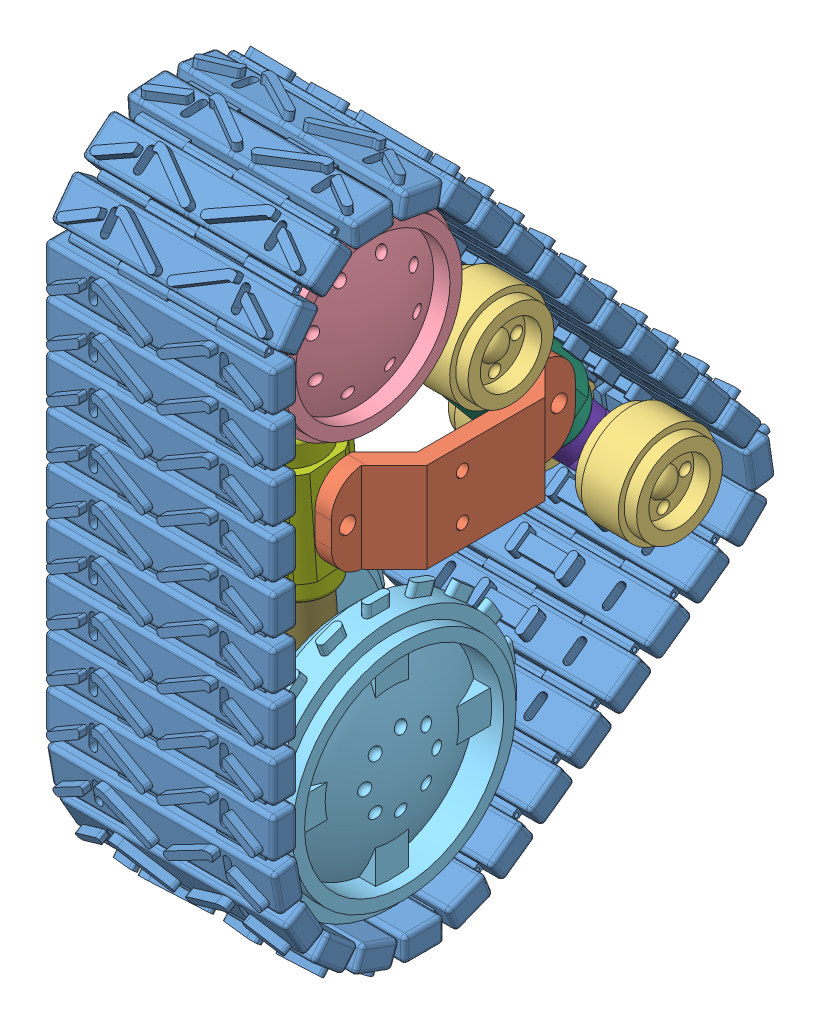
SolidWorks assembly Right Side Drive Train, configuration Default. Lengths in mm.
Overall size (45.17 135.4 102.97).
53 component instances, 12 part files, 148 mates.
Components (placement in the parent):
- Track segment-1: Track segment [Default] at origin size (45.17 8.87 11.14)
- Track segment-2: Track segment [Default] at (0 1.7763 10.0644) x (1 0 0) z (0 0.34232 0.939583) size (45.17 8.87 11.14)
- Track segment-3: Track segment [Default] at (0 34.1905 29.8413) x (1 0 0) z (0 1 0) size (45.17 8.87 11.14)
- Track segment-4: Track segment [Default] at (0 43.7144 29.8413) x (1 0 0) z (0 1 0) size (45.17 8.87 11.14)
- Track segment-5: Track segment [Default] at (0 53.2383 29.8413) x (1 0 0) z (0 1 0) size (45.17 8.87 11.14)
- Track segment-6: Track segment [Default] at (0 6.8872 18.9134) x (1 0 0) z (0 0.642788 0.766044) size (45.17 8.87 11.14)
- Track segment-7: Track segment [Default] at (0 14.7157 25.4824) x (1 0 0) z (0 0.866025 0.5) size (45.17 8.87 11.14)
- Track segment-8: Track segment [Default] at (0 24.3188 28.9776) x (1 0 0) z (0 0.984808 0.173648) size (45.17 8.87 11.14)
- Track segment-9: Track segment [Default] at (0 62.7622 29.8413) x (1 0 0) z (0 1 0) size (45.17 8.87 11.14)
- Track segment-10: Track segment [Default] at (0 72.2861 29.8413) x (1 0 0) z (0 1 0) size (45.17 8.87 11.14)
- Track segment-11: Track segment [Default] at (0 81.81 29.8413) x (1 0 0) z (0 1 0) size (45.17 8.87 11.14)
- Track segment-12: Track segment [Default] at (0 91.3339 29.8413) x (1 0 0) z (0 1 0) size (45.17 8.87 11.14)
- Track segment-13: Track segment [Default] at (0 100.8578 29.8413) x (1 0 0) z (0 1 0) size (45.17 8.87 11.14)
- Track segment-14: Track segment [Default] at (0 110.3817 29.8413) x (1 0 0) z (0 1 0) size (45.17 8.87 11.14)
- Track segment-15: Track segment [Default] at (0 127.7384 19.6963) x (1 0 0) z (0 0.642298 -0.766455) size (45.17 8.87 11.14)
- Track segment-16: Track segment [Default] at (0 131.6664 9.8979) x (1 0 0) z (0 0.064998 -0.997885) size (45.17 8.87 11.14)
- Track segment-17: Track segment [Default] at (0 131.1108 -0.123) x (1 0 0) z (0 -0.174908 -0.984585) size (45.17 8.87 11.14)
- Track segment-18: Track segment [Default] at (0 126.1238 -9.4271) x (1 0 0) z (0 -0.723087 -0.690757) size (45.17 8.87 11.14)
- Track segment-19: Track segment [Default] at (0 118.8782 -15.8648) x (1 0 0) z (0 -0.771041 -0.636786) size (45.17 8.87 11.14)
- Track segment-20: Track segment [Default] at (0 111.5349 -21.9295) x (1 0 0) z (0 -0.771041 -0.636786) size (45.17 8.87 11.14)
- Track segment-21: Track segment [Default] at (0 82.1919 -46.2013) x (1 0 0) z (0 -0.767095 -0.641534) size (45.17 8.87 11.14)
- Track segment-22: Track segment [Default] at (0 120.4147 26.5585) x (1 0 0) z (0 0.806583 -0.591121) size (45.17 8.87 11.14)
- Track segment-23: Track segment [Default] at (0 34.4794 -57.6062) x (1 0 0) z (0 -0.582062 0.813145) size (45.17 8.87 11.14)
- Track segment-24: Track segment [Default] at (0 104.1916 -27.9942) x (1 0 0) z (0 -0.771041 -0.636786) size (45.17 8.87 11.14)
- Track segment-25: Track segment [Default] at (0 96.8483 -34.0588) x (1 0 0) z (0 -0.77104 -0.636786) size (45.17 8.87 11.14)
- Track segment-26: Track segment [Default] at (0 89.505 -40.1235) x (1 0 0) z (0 -0.77104 -0.636786) size (45.17 8.87 11.14)
- Track segment-27: Track segment [Default] at (0 74.8862 -52.3112) x (1 0 0) z (0 -0.767095 -0.641534) size (45.17 8.87 11.14)
- Track segment-28: Track segment [Default] at (0 67.5805 -58.4211) x (1 0 0) z (0 -0.767095 -0.641534) size (45.17 8.87 11.14)
- Track segment-29: Track segment [Default] at (0 60.2747 -64.531) x (1 0 0) z (0 -0.767095 -0.641534) size (45.17 8.87 11.14)
- Track segment-30: Track segment [Default] at (0 50.7132 -68.8203) x (1 0 0) z (0 -0.989231 -0.146359) size (45.17 8.87 11.14)
- Track segment-31: Track segment [Default] at (0 40.5787 -65.4426) x (1 0 0) z (0 -0.703629 0.710567) size (45.17 8.87 11.14)
- Track segment-32: Track segment [Default] at (0 28.9359 -49.8619) x (1 0 0) z (0 -0.582062 0.813145) size (45.17 8.87 11.14)
- Track segment-33: Track segment [Default] at (0 17.8489 -34.3733) x (1 0 0) z (0 -0.582062 0.813145) size (45.17 8.87 11.14)
- Track segment-34: Track segment [Default] at (0 23.3924 -42.1176) x (1 0 0) z (0 -0.582062 0.813145) size (45.17 8.87 11.14)
- Track segment-35: Track segment [Default] at (0 12.3054 -26.6289) x (1 0 0) z (0 -0.582062 0.813145) size (45.17 8.87 11.14)
- Track segment-36: Track segment [Default] at (0 6.7619 -18.8846) x (1 0 0) z (0 -0.582062 0.813144) size (45.17 8.87 11.14)
- Track segment-37: Track segment [Default] at (0 1.9422 -10.0819) x (1 0 0) z (0 -0.371493 0.928436) size (45.17 8.87 11.14)
- Bracket-1: Bracket [Default] at (12.0993 68.7945 -17.7388) x (0 1 0) z (-1 0 0) size (17.74 48.1 9.68)
- Tensioner Small-1: Tensioner Small [Default] at (-12.5006 89.8246 -21.0494) x (0 -0.325213 -0.945641) z (-1 0 0) size (19.33 19.33 12.1)
- Tensioner Large-1: Tensioner Large [Default] at (12.4939 108.1911 6.1736) x (0 -0.888344 -0.459179) z (1 0 0) size (37.66 37.66 12.1)
- Drive Sprocket-1: Drive Sprocket [Default] at (12.907 29.4005 0) x (0 0 1) z (1 0 0) size (53.82 53.8 11.29)
- Cylinder Small-1: Cylinder Small [Default] at (0.0013 68.7945 -38.5642) x (0 -0.768404 -0.639964) z (1 0 0) size (29.03 16.13 14.52)
- Cylinder Large-1: Cylinder Large [Default] at (0.0013 68.7945 3.0867) x (0 -0.996944 -0.078115) z (1 0 0) size (29.03 17.74 14.52)
- Axle short-1: Axle short [Default] at (0.0013 69.8778 -37.6621) x (0 0.768404 0.639964) z (-1 0 0) size (61.59 9.68 12.1)
- Shock Absorber Guide-1: Shock Absorber Guide [Default] at (-10.4838 68.7945 17.1387) x (0 1 0) z (-1 0 0) size (25.81 15.73 9.28)
- Shock Absorber Pivot-1: Shock Absorber Pivot [Default] at (-9.6787 68.7945 3.0867) x (0 1 0) z (-1 0 0) size (19.38 11.58 8.47)
- Shock Absorber Spring-1: Shock Absorber Spring [Default] at (-12.5006 68.7945 20.9691) x (0.879385 -0.476111 0) z (0.476111 0.879385 0) size (5.09 14.18 4.84)
- Tensioner Small-2: Tensioner Small [Default] at (12.5031 89.8246 -21.0494) x (0 -1 0.00019) z (1 0 0) size (19.33 19.33 12.1)
- Tensioner Large-2: Tensioner Large [Default] at (-12.4914 108.1911 6.1736) x (0 -0.876526 0.481354) z (-1 0 0) size (37.66 37.66 12.1)
- Drive Sprocket-2: Drive Sprocket [Default] at (-12.9045 29.4005 0) x (0 0 1) z (-1 0 0) size (53.82 53.8 11.29)
- Tensioner Small-3: Tensioner Small [Default] at (-12.5006 49.9309 -54.2748) x (0 1 0) z (-1 0 0) size (19.33 19.33 12.1)
- Tensioner Small-4: Tensioner Small [Default] at (12.5031 49.9309 -54.2748) x (0 -1 0) z (1 0 0) size (19.33 19.33 12.1)
- Axle long-1: Axle long [Default] at (0.0013 68.7958 3.0868) x (0 -0.996944 -0.078115) z (1 0 0) size (90.32 12.9 13.71)
Mates (geometry in assembly coordinates):
- Concentric61: concentric: cylinder of assembly; cylinder of assembly; cylinder of Track segment-1 through (-9.6774 2.4194 4.7619) axis (1 0 0) radius 0.4039; cylinder of Track segment-2 through (-9.6774 2.4194 4.7619) axis (-1 0 0) radius 0.4039
- Coincident54: coincident: plane of assembly; plane of assembly; plane of Track segment-1 through (-9.6774 2.4194 4.7619) normal (-1 0 0); plane of Track segment-2 through (-9.6774 2.4194 4.7619) normal (1 0 0)
- Perpendicular2: perpendicular: plane of assembly; plane of assembly; plane of Track segment-1 through (0 0 0) normal (0 -1 0); plane of Track segment-3 through (0 34.1905 29.8413) normal (0 0 1)
- Concentric106: concentric: cylinder of assembly; cylinder of assembly; cylinder of Track segment-1 through (-9.6774 2.4193 -4.7619) axis (-1 0 0) radius 0.4039; cylinder of Track segment-37 through (-9.6774 2.4193 -4.7619) axis (1 0 0) radius 0.4039
- Coincident103: coincident: plane of assembly; plane of assembly; plane of Track segment-1 through (9.6774 2.4193 -4.7619) normal (1 0 0); plane of Track segment-37 through (9.6774 2.4193 -4.7619) normal (-1 0 0)
- Concentric62: concentric: cylinder of assembly; cylinder of assembly; cylinder of Track segment-2 through (-9.6774 5.6796 13.7104) axis (1 0 0) radius 0.4039; cylinder of Track segment-6 through (-9.6774 5.6796 13.7104) axis (-1 0 0) radius 0.4039
- Coincident56: coincident: plane of assembly; plane of assembly; plane of Track segment-2 through (0 5.6796 13.7104) normal (1 0 0); plane of Track segment-6 through (0 5.6796 13.7104) normal (-1 0 0)
- Concentric66: concentric: cylinder of assembly; cylinder of assembly; cylinder of Track segment-3 through (-9.6774 29.4286 27.4219) axis (-1 0 0) radius 0.4039; cylinder of Track segment-8 through (-9.6774 29.4286 27.4219) axis (1 0 0) radius 0.4039
- Coincident61: coincident: plane of assembly; plane of assembly; plane of Track segment-3 through (-9.6774 29.4286 27.4219) normal (1 0 0); plane of Track segment-8 through (-9.6774 29.4286 27.4219) normal (-1 0 0)
- Concentric68: concentric: cylinder of assembly; cylinder of assembly; cylinder of Track segment-3 through (-9.6774 38.9525 27.4219) axis (1 0 0) radius 0.4039; cylinder of Track segment-4 through (-9.6774 38.9525 27.4219) axis (-1 0 0) radius 0.4039
- Coincident62: coincident: plane of Track segment-3 through (0 38.9525 27.4219) normal (1 0 0); plane of Track segment-4 through (0 38.9525 27.4219) normal (-1 0 0)
- Concentric70: concentric: cylinder of Track segment-4 through (9.6774 48.4764 27.4219) axis (1 0 0) radius 0.4039; cylinder of Track segment-5 through (9.6774 48.4764 27.4219) axis (-1 0 0) radius 0.4039
- Coincident67: coincident: plane of Track segment-4 through (-9.6774 48.4764 27.4219) normal (-1 0 0); plane of Track segment-5 through (-9.6774 48.4764 27.4219) normal (1 0 0)
- Concentric71: concentric: cylinder of Track segment-5 through (-9.6774 58.0003 27.4219) axis (1 0 0) radius 0.4039; cylinder of Track segment-9 through (-9.6774 58.0003 27.4219) axis (-1 0 0) radius 0.4039
- Coincident68: coincident: plane of Track segment-5 through (0 58.0003 27.4219) normal (1 0 0); plane of Track segment-9 through (0 58.0003 27.4219) normal (-1 0 0)
- Concentric64: concentric: cylinder of assembly; cylinder of assembly; cylinder of Track segment-6 through (9.6774 11.8014 21.0062) axis (1 0 0) radius 0.4039; cylinder of Track segment-7 through (9.6774 11.8014 21.0062) axis (-1 0 0) radius 0.4039
- Coincident57: coincident: plane of Track segment-6 through (0 11.8014 21.0062) normal (1 0 0); plane of Track segment-7 through (0 11.8014 21.0062) normal (-1 0 0)
- Concentric65: concentric: cylinder of Track segment-7 through (-9.6774 20.0494 25.7681) axis (1 0 0) radius 0.4039; cylinder of Track segment-8 through (-9.6774 20.0494 25.7681) axis (-1 0 0) radius 0.4039
- Coincident59: coincident: plane of Track segment-7 through (0 20.0494 25.7681) normal (1 0 0); plane of Track segment-8 through (0 20.0494 25.7681) normal (-1 0 0)
- Concentric72: concentric: cylinder of Track segment-9 through (-9.6774 67.5242 27.4219) axis (1 0 0) radius 0.4039; cylinder of Track segment-10 through (-9.6774 67.5242 27.4219) axis (-1 0 0) radius 0.4039
- Coincident69: coincident: plane of Track segment-9 through (-9.6774 67.5242 27.4219) normal (-1 0 0); plane of Track segment-10 through (-9.6774 67.5242 27.4219) normal (1 0 0)
- Concentric73: concentric: cylinder of Track segment-10 through (-9.6774 77.0481 27.4219) axis (1 0 0) radius 0.4039; cylinder of Track segment-11 through (9.6774 77.0481 27.4219) axis (-1 0 0) radius 0.4039
- Coincident70: coincident: plane of Track segment-10 through (-9.6774 77.0481 27.4219) normal (-1 0 0); plane of Track segment-11 through (-9.6774 77.0481 27.4219) normal (1 0 0)
- Concentric74: concentric: cylinder of Track segment-11 through (-9.6774 86.572 27.4219) axis (1 0 0) radius 0.4039; cylinder of Track segment-12 through (-9.6774 86.572 27.4219) axis (-1 0 0) radius 0.4039
- Coincident71: coincident: plane of Track segment-11 through (-9.6774 86.572 27.4219) normal (-1 0 0); plane of Track segment-12 through (-9.6774 86.572 27.4219) normal (1 0 0)
- Concentric75: concentric: cylinder of Track segment-12 through (-9.6774 96.0959 27.4219) axis (1 0 0) radius 0.4039; cylinder of Track segment-13 through (-9.6774 96.0959 27.4219) axis (-1 0 0) radius 0.4039
- Coincident72: coincident: plane of Track segment-12 through (-9.6774 96.0959 27.4219) normal (-1 0 0); plane of Track segment-13 through (-9.6774 96.0959 27.4219) normal (1 0 0)
- Concentric76: concentric: cylinder of Track segment-13 through (-9.6774 105.6198 27.4219) axis (1 0 0) radius 0.4039; cylinder of Track segment-14 through (-9.6774 105.6198 27.4219) axis (-1 0 0) radius 0.4039
- Coincident73: coincident: plane of Track segment-13 through (-9.6774 105.6198 27.4219) normal (-1 0 0); plane of Track segment-14 through (-9.6774 105.6198 27.4219) normal (1 0 0)
- Concentric77: concentric: cylinder of Track segment-14 through (-9.6774 115.1437 27.4219) axis (1 0 0) radius 0.4039; cylinder of Track segment-22 through (-9.6774 115.1437 27.4219) axis (-1 0 0) radius 0.4039
- Coincident74: coincident: plane of Track segment-14 through (-9.6774 115.1437 27.4219) normal (-1 0 0); plane of Track segment-22 through (-9.6774 115.1437 27.4219) normal (1 0 0)
- Concentric78: concentric: cylinder of Track segment-15 through (-9.6774 122.8255 21.7922) axis (-1 0 0) radius 0.4039; cylinder of Track segment-22 through (-9.6774 122.8255 21.7922) axis (1 0 0) radius 0.4039
- Coincident75: coincident: plane of Track segment-15 through (-9.6774 122.8255 21.7922) normal (1 0 0); plane of Track segment-22 through (-9.6774 122.8255 21.7922) normal (-1 0 0)
- Concentric79: concentric: cylinder of Track segment-15 through (-9.6774 128.9426 14.4925) axis (1 0 0) radius 0.4039; cylinder of Track segment-16 through (-9.6774 128.9426 14.4925) axis (-1 0 0) radius 0.4039
- Coincident76: coincident: plane of Track segment-15 through (-9.6774 128.9426 14.4925) normal (-1 0 0); plane of Track segment-16 through (-9.6774 128.9426 14.4925) normal (1 0 0)
- Concentric80: concentric: cylinder of Track segment-16 through (-9.6774 129.5617 4.9888) axis (1 0 0) radius 0.4039; cylinder of Track segment-17 through (9.6774 129.5617 4.9888) axis (-1 0 0) radius 0.4039
- Coincident77: coincident: plane of Track segment-16 through (-9.6774 129.5617 4.9888) normal (-1 0 0); plane of Track segment-17 through (-9.6774 129.5617 4.9888) normal (1 0 0)
- Concentric81: concentric: cylinder of Track segment-17 through (9.6774 127.8959 -4.3883) axis (1 0 0) radius 0.4039; cylinder of Track segment-18 through (9.6774 127.8959 -4.3883) axis (-1 0 0) radius 0.4039
- Coincident78: coincident: plane of Track segment-17 through (-9.6774 127.8959 -4.3883) normal (-1 0 0); plane of Track segment-18 through (-9.6774 127.8959 -4.3883) normal (1 0 0)
- Concentric82: concentric: cylinder of Track segment-18 through (9.6774 121.0093 -10.967) axis (1 0 0) radius 0.4039; cylinder of Track segment-19 through (9.6774 121.0093 -10.967) axis (-1 0 0) radius 0.4039
- Coincident79: coincident: plane of Track segment-18 through (9.6774 121.0093 -10.967) normal (-1 0 0); plane of Track segment-19 through (9.6774 121.0093 -10.967) normal (1 0 0)
- Concentric83: concentric: cylinder of Track segment-19 through (9.6774 113.666 -17.0317) axis (1 0 0) radius 0.4039; cylinder of Track segment-20 through (9.6774 113.666 -17.0317) axis (-1 0 0) radius 0.4039
- Coincident80: coincident: plane of Track segment-19 through (9.6774 113.666 -17.0317) normal (-1 0 0); plane of Track segment-20 through (9.6774 113.666 -17.0317) normal (1 0 0)
- Parallel34: parallel: plane of Track segment-19 through (0 118.8782 -15.8648) normal (0 0.636786 -0.771041); plane of Track segment-20 through (0 111.5349 -21.9295) normal (0 0.636786 -0.771041)
- Concentric104: concentric: cylinder of Track segment-20 through (9.6774 106.3226 -23.0964) axis (1 0 0) radius 0.4039; cylinder of Track segment-24 through (9.6774 106.3226 -23.0964) axis (-1 0 0) radius 0.4039
- Coincident102: coincident: plane of Track segment-20 through (0 106.3226 -23.0964) normal (1 0 0); plane of Track segment-24 through (0 106.3226 -23.0964) normal (-1 0 0)
- Coincident88: coincident: plane of assembly; plane of assembly; plane of Track segment-21 through (0 84.2927 -41.2905) normal (-1 0 0); plane of Track segment-26 through (0 84.2927 -41.2905) normal (1 0 0)
- Concentric90: concentric: cylinder of assembly; cylinder of assembly; cylinder of Track segment-21 through (-9.6774 84.2927 -41.2905) axis (-1 0 0) radius 0.4039; cylinder of Track segment-26 through (-9.6774 84.2927 -41.2905) axis (1 0 0) radius 0.4039
- Concentric91: concentric: cylinder of assembly; cylinder of assembly; cylinder of Track segment-21 through (-9.6774 76.987 -47.4004) axis (1 0 0) radius 0.4039; cylinder of Track segment-27 through (-9.6774 76.987 -47.4004) axis (-1 0 0) radius 0.4039
- Coincident89: coincident: plane of assembly; plane of assembly; plane of Track segment-21 through (0 76.987 -47.4004) normal (1 0 0); plane of Track segment-27 through (0 76.987 -47.4004) normal (-1 0 0)
- Concentric108: concentric: cylinder of assembly; cylinder of assembly; cylinder of Track segment-23 through (-9.6774 33.6749 -52.3258) axis (1 0 0) radius 0.4039; cylinder of Track segment-32 through (-9.6774 33.6749 -52.3258) axis (-1 0 0) radius 0.4039
- Coincident105: coincident: plane of assembly; plane of assembly; plane of Track segment-23 through (9.6774 33.6749 -52.3258) normal (-1 0 0); plane of Track segment-32 through (9.6774 33.6749 -52.3258) normal (1 0 0)
- Parallel38: parallel: plane of assembly; plane of assembly; plane of Track segment-23 through (0 34.4794 -57.6062) normal (0 -0.813145 -0.582062); plane of Track segment-32 through (0 28.9359 -49.8619) normal (0 -0.813145 -0.582062)
- Concentric84: concentric: cylinder of assembly; cylinder of assembly; cylinder of Track segment-24 through (-9.6774 98.9793 -29.1611) axis (1 0 0) radius 0.4039; cylinder of Track segment-25 through (-9.6774 98.9793 -29.1611) axis (-1 0 0) radius 0.4039
- Coincident83: coincident: plane of assembly; plane of assembly; plane of Track segment-24 through (9.6774 98.9793 -29.1611) normal (-1 0 0); plane of Track segment-25 through (9.6774 98.9793 -29.1611) normal (1 0 0)
- Coincident84: coincident: plane of assembly; plane of assembly; plane of Track segment-25 through (0 91.636 -35.2258) normal (1 0 0); plane of Track segment-26 through (0 91.636 -35.2258) normal (-1 0 0)
- Concentric88: concentric: cylinder of assembly; cylinder of assembly; cylinder of Track segment-25 through (9.6774 91.636 -35.2258) axis (1 0 0) radius 0.4039; cylinder of Track segment-26 through (9.6774 91.636 -35.2258) axis (-1 0 0) radius 0.4039
- Concentric92: concentric: cylinder of assembly; cylinder of assembly; cylinder of Track segment-27 through (-9.6774 69.6812 -53.5103) axis (1 0 0) radius 0.4039; cylinder of Track segment-28 through (-9.6774 69.6812 -53.5103) axis (-1 0 0) radius 0.4039
- Coincident90: coincident: plane of Track segment-27 through (-9.6774 69.6812 -53.5103) normal (-1 0 0); plane of Track segment-28 through (-9.6774 69.6812 -53.5103) normal (1 0 0)
- Concentric94: concentric: cylinder of Track segment-28 through (-9.6774 62.3755 -59.6202) axis (1 0 0) radius 0.4039; cylinder of Track segment-29 through (-9.6774 62.3755 -59.6202) axis (-1 0 0) radius 0.4039
- Coincident91: coincident: plane of Track segment-28 through (-9.6774 62.3755 -59.6202) normal (-1 0 0); plane of Track segment-29 through (-9.6774 62.3755 -59.6202) normal (1 0 0)
- Concentric95: concentric: cylinder of Track segment-29 through (-9.6774 55.0698 -65.7301) axis (1 0 0) radius 0.4039; cylinder of Track segment-30 through (-9.6774 55.0698 -65.7301) axis (-1 0 0) radius 0.4039
- Coincident93: coincident: plane of Track segment-29 through (-9.6774 55.0698 -65.7301) normal (-1 0 0); plane of Track segment-30 through (-9.6774 55.0698 -65.7301) normal (1 0 0)
- Concentric96: concentric: cylinder of Track segment-30 through (-9.6774 45.6484 -67.124) axis (1 0 0) radius 0.4039; cylinder of Track segment-31 through (-9.6774 45.6484 -67.124) axis (-1 0 0) radius 0.4039
- Coincident94: coincident: plane of Track segment-30 through (-9.6774 45.6484 -67.124) normal (-1 0 0); plane of Track segment-31 through (-9.6774 45.6484 -67.124) normal (1 0 0)
- Concentric99: concentric: cylinder of assembly; cylinder of assembly; cylinder of Track segment-32 through (-9.6774 28.1314 -44.5815) axis (1 0 0) radius 0.4039; cylinder of Track segment-34 through (-9.6774 28.1314 -44.5815) axis (-1 0 0) radius 0.4039
- Coincident97: coincident: plane of Track segment-32 through (-9.6774 28.1314 -44.5815) normal (-1 0 0); plane of Track segment-34 through (-9.6774 28.1314 -44.5815) normal (1 0 0)
- Concentric100: concentric: cylinder of Track segment-33 through (-9.6774 22.5879 -36.8372) axis (-1 0 0) radius 0.4039; cylinder of Track segment-34 through (-9.6774 22.5879 -36.8372) axis (1 0 0) radius 0.4039
- Coincident98: coincident: plane of Track segment-33 through (-9.6774 22.5879 -36.8372) normal (1 0 0); plane of Track segment-34 through (-9.6774 22.5879 -36.8372) normal (-1 0 0)
- Concentric101: concentric: cylinder of Track segment-33 through (-9.6774 17.0444 -29.0929) axis (1 0 0) radius 0.4039; cylinder of Track segment-35 through (-9.6774 17.0444 -29.0929) axis (-1 0 0) radius 0.4039
- Coincident99: coincident: plane of Track segment-33 through (-9.6774 17.0444 -29.0929) normal (-1 0 0); plane of Track segment-35 through (-9.6774 17.0444 -29.0929) normal (1 0 0)
- Concentric102: concentric: cylinder of Track segment-35 through (9.6774 11.5009 -21.3486) axis (1 0 0) radius 0.4039; cylinder of Track segment-36 through (9.6774 11.5009 -21.3486) axis (-1 0 0) radius 0.4039
- Coincident100: coincident: plane of Track segment-35 through (0 11.5009 -21.3486) normal (1 0 0); plane of Track segment-36 through (0 11.5009 -21.3486) normal (-1 0 0)
- Concentric103: concentric: cylinder of Track segment-36 through (9.6774 5.9574 -13.6043) axis (1 0 0) radius 0.4039; cylinder of Track segment-37 through (9.6774 5.9574 -13.6043) axis (-1 0 0) radius 0.4039
- Coincident101: coincident: plane of Track segment-36 through (0 5.9574 -13.6043) normal (1 0 0); plane of Track segment-37 through (0 5.9574 -13.6043) normal (-1 0 0)
- Parallel24: parallel: plane of assembly; plane of assembly; plane of Bracket-1 through (7.2606 59.9223 -41.79) normal (-1 0 0); plane of Tensioner Small-2 through (18.5534 89.823 -29.505) normal (1 0 0)
- Concentric49: concentric: cylinder of Bracket-1 through (16.938 68.7945 -38.5642) axis (-1 0 0) radius 1.6129; cylinder of Cylinder Small-1 through (6.0515 68.7945 -38.5642) axis (1 0 0) radius 1.6129
- Coincident50: coincident: plane of Bracket-1 through (7.2606 59.9223 -41.79) normal (-1 0 0); plane of Cylinder Small-1 through (7.2606 78.4786 -35.0702) normal (1 0 0)
- Concentric57: concentric: cylinder of Bracket-1 through (16.938 68.7945 3.0867) axis (-1 0 0) radius 1.6129; cylinder of Cylinder Large-1 through (6.0515 68.7945 3.0867) axis (1 0 0) radius 1.651
- Coincident52: coincident: plane of Bracket-1 through (7.2606 59.9223 6.3125) normal (-1 0 0); plane of Cylinder Large-1 through (7.2606 78.7168 0.3408) normal (1 0 0)
- Distance17: distance = 27.3685 mm: line of Axle short-1 through (6.0503 89.8246 -21.0494) axis (-1 0 0); axis of Bracket-1 through (10.4864 68.7945 -38.5642) axis (-1 0 0)
- Concentric45: concentric: cylinder of Tensioner Small-1 through (-16.9354 89.8246 -21.0494) axis (-1 0 0) radius 3.2258; cylinder of Tensioner Small-2 through (16.938 89.8246 -21.0494) axis (1 0 0) radius 3.2258
- Distance8: distance = 12.9032 mm: plane of Tensioner Small-1 through (-6.4503 86.7742 -20.0003) normal (1 0 0); plane of Tensioner Small-2 through (6.4529 89.824 -24.2752) normal (-1 0 0)
- Tangent95: tangent: cylinder of Tensioner Small-1 through (-16.9354 89.8246 -21.0494) axis (-1 0 0) radius 9.6647; plane of Track segment-19 through (0 115.797 -12.134) normal (0 -0.636786 0.771041)
- Tangent96: tangent: cylinder of Tensioner Small-1 through (-16.9354 89.8246 -21.0494) axis (-1 0 0) radius 9.6647; plane of Track segment-20 through (0 108.4537 -18.1986) normal (0 -0.636786 0.771041)
- Tangent99: tangent: cylinder of Tensioner Small-1 through (-16.9354 89.8246 -21.0494) axis (-1 0 0) radius 9.6647; plane of Track segment-24 through (0 101.1104 -24.2633) normal (0 -0.636786 0.771041)
- Tangent100: tangent: cylinder of Tensioner Small-1 through (-16.9354 89.8246 -21.0494) axis (-1 0 0) radius 9.6647; plane of Track segment-25 through (0 93.7671 -30.328) normal (0 -0.636786 0.77104)
- Tangent101: tangent: cylinder of Tensioner Small-1 through (-16.9354 89.8246 -21.0494) axis (-1 0 0) radius 9.6647; plane of Track segment-26 through (0 86.4237 -36.3927) normal (0 -0.636786 0.77104)
- Concentric54: concentric: cylinder of assembly; cylinder of assembly; cylinder of Tensioner Large-1 through (18.5429 108.1911 6.1736) axis (1 0 0) radius 3.2304; cylinder of Tensioner Large-2 through (-18.5404 108.1911 6.1736) axis (-1 0 0) radius 3.2304; cone of assembly; axis of ?
- Distance12: distance = 12.9032 mm: cone of Tensioner Large-2 through (-6.4424 108.1911 6.1736) axis (-1 0 0); cylinder of Tensioner Large-1 through (6.4449 108.1911 6.1736) axis (1 0 0) radius 1570.2717
- Parallel25: parallel: cylinder of Tensioner Large-1 through (6.4449 108.1911 6.1736) axis (1 0 0) radius 1570.2717; cylinder of Tensioner Large-2 through (-6.4424 108.1911 6.1736) axis (-1 0 0) radius 1570.2717
- Concentric56: concentric: cylinder of Tensioner Large-1 through (18.5429 108.1911 6.1736) axis (1 0 0) radius 3.2304; cylinder of Axle long-1 through (-6.1874 108.1911 6.1736) axis (1 0 0) radius 3.2258
- Concentric58: concentric: cylinder of assembly; cylinder of assembly; cylinder of Drive Sprocket-1 through (18.5534 29.4005 0) axis (1 0 0) radius 4.8387; cylinder of Drive Sprocket-2 through (-18.5509 29.4005 0) axis (-1 0 0) radius 4.8387
- Parallel27: parallel: plane of Drive Sprocket-1 through (7.2606 24.5618 0) normal (-1 0 0); plane of Drive Sprocket-2 through (-7.258 34.2392 0) normal (1 0 0)
- Distance13: distance = 14.5186 mm: plane of Drive Sprocket-1 through (7.2606 24.5618 0) normal (-1 0 0); plane of Drive Sprocket-2 through (-7.258 34.2392 0) normal (1 0 0)
- Parallel28: parallel: plane of Drive Sprocket-1 through (12.907 56.2991 1.6129) normal (0 1 0); plane of Drive Sprocket-2 through (-12.9045 56.2991 -1.6129) normal (0 1 0)
- Concentric50: concentric: cylinder of Cylinder Small-1 through (0.0013 79.9488 -29.2745) axis (0 -0.768404 -0.639964) radius 4.8387; cylinder of Axle short-1 through (0.0013 49.9309 -54.2748) axis (0 0.768404 0.639964) radius 4.8387
- Concentric52: concentric: cylinder of Cylinder Large-1 through (0.0013 83.2663 4.2206) axis (0 -0.996944 -0.078115) radius 4.8387; cylinder of Axle long-1 through (0.0013 108.1911 6.1736) axis (0 -0.996944 -0.078115) radius 4.8387
- Parallel26: parallel: plane of Cylinder Large-1 through (-7.258 78.7168 0.3408) normal (-1 0 0); plane of Axle long-1 through (-6.8542 29.4005 0) normal (-1 0 0)
- Distance16: distance = 39.5173 mm: line of Cylinder Large-1 through (-6.049 68.7945 3.0867) axis (-1 0 0); line of Axle long-1 through (-6.1874 108.1911 6.1736) axis (1 0 0)
- Coincident109: coincident: plane of Cylinder Large-1 through (-7.258 78.7168 0.3408) normal (-1 0 0); plane of Shock Absorber Pivot-1 through (-7.258 60.7173 6.602) normal (1 0 0)
- Concentric114: concentric: cylinder of Cylinder Large-1 through (-6.049 68.7945 3.0867) axis (-1 0 0) radius 1.651; cylinder of Shock Absorber Pivot-1 through (-7.258 68.7945 3.0867) axis (-1 0 0) radius 1.6129
- Concentric47: concentric: cylinder of Axle short-1 through (6.0503 89.8246 -21.0494) axis (-1 0 0) radius 3.2258; cylinder of Tensioner Small-2 through (16.938 89.8246 -21.0494) axis (1 0 0) radius 3.2258
- Concentric48: concentric: cylinder of Axle short-1 through (6.0503 49.9309 -54.2748) axis (-1 0 0) radius 3.2258; cylinder of Tensioner Small-4 through (16.938 49.9309 -54.2748) axis (1 0 0) radius 3.2258
- Width23: width: plane of Tensioner Small-4 through (6.4529 49.9309 -57.5006) normal (-1 0 0); plane of Tensioner Small-3 through (-6.4503 49.9309 -57.5006) normal (1 0 0); plane of Axle short-1 through (6.0503 49.9309 -54.2748) normal (1 0 0); plane of Axle short-1 through (-6.0477 49.9309 -54.2748) normal (-1 0 0)
- Width24: width: plane of Tensioner Small-2 through (6.4529 89.824 -24.2752) normal (-1 0 0); plane of Tensioner Small-1 through (-6.4503 86.7742 -20.0003) normal (1 0 0); plane of Axle short-1 through (6.0503 89.8246 -21.0494) normal (1 0 0); plane of Axle short-1 through (-6.0477 89.8246 -21.0494) normal (-1 0 0)
- Concentric113: concentric: cylinder of Shock Absorber Guide-1 through (-12.5006 68.7945 20.9691) axis (0 0 -1) radius 2.4206; cylinder of Shock Absorber Pivot-1 through (-12.5006 68.7945 7.4072) axis (0 0 1) radius 2.4206
- Parallel41: parallel: plane of Shock Absorber Guide-1 through (-15.7264 68.7945 17.1387) normal (-1 0 0); plane of Shock Absorber Pivot-1 through (-9.6787 60.7173 6.602) normal (-1 0 0)
- Coincident111: coincident: plane of Shock Absorber Guide-1 through (-12.5006 68.7945 20.9691) normal (0 0 -1); plane of Shock Absorber Spring-1 through (-12.5006 68.7945 20.9691) normal (0 0 -1)
- Concentric115: concentric: circle of Shock Absorber Guide-1; unknown of Shock Absorber Spring-1
- Coincident112: coincident: plane of Shock Absorber Guide-1 through (-15.7264 59.9223 25.0026) normal (0 0 1); plane of Track segment-10 through (0 72.2861 25.0026) normal (0 0 -1)
- Width26: width: plane of Tensioner Large-2 through (-8.8617 117.2545 22.6777) normal (1 0 0); plane of Tensioner Large-1 through (8.8642 116.837 -10.5531) normal (-1 0 0); plane of Axle long-1 through (6.19 108.1911 6.1736) normal (1 0 0); plane of Axle long-1 through (-6.1874 108.1911 6.1736) normal (-1 0 0)
- Tangent82: tangent: cylinder of Tensioner Large-2 through (-18.5404 108.1911 6.1736) axis (-1 0 0) radius 18.829; plane of Track segment-3 through (0 34.1905 25.0026) normal (0 0 -1)
- Tangent83: tangent: cylinder of Tensioner Large-2 through (-18.5404 108.1911 6.1736) axis (-1 0 0) radius 18.829; plane of Track segment-4 through (0 43.7144 25.0026) normal (0 0 -1)
- Tangent84: tangent: cylinder of Tensioner Large-2 through (-18.5404 108.1911 6.1736) axis (-1 0 0) radius 18.829; plane of Track segment-5 through (0 53.2383 25.0026) normal (0 0 -1)
- Tangent85: tangent: cylinder of Tensioner Large-2 through (-18.5404 108.1911 6.1736) axis (-1 0 0) radius 18.829; plane of Track segment-9 through (0 62.7622 25.0026) normal (0 0 -1)
- Tangent86: tangent: cylinder of Tensioner Large-2 through (-18.5404 108.1911 6.1736) axis (-1 0 0) radius 18.829; plane of Track segment-10 through (0 72.2861 25.0026) normal (0 0 -1)
- Tangent87: tangent: cylinder of Tensioner Large-2 through (-18.5404 108.1911 6.1736) axis (-1 0 0) radius 18.829; plane of Track segment-11 through (0 81.81 25.0026) normal (0 0 -1)
- Tangent88: tangent: cylinder of Tensioner Large-2 through (-18.5404 108.1911 6.1736) axis (-1 0 0) radius 18.829; plane of Track segment-12 through (0 91.3339 25.0026) normal (0 0 -1)
- Tangent89: tangent: cylinder of Tensioner Large-2 through (-18.5404 108.1911 6.1736) axis (-1 0 0) radius 18.829; plane of Track segment-13 through (0 100.8578 25.0026) normal (0 0 -1)
- Tangent90: tangent: cylinder of Tensioner Large-2 through (-18.5404 108.1911 6.1736) axis (-1 0 0) radius 18.829; plane of Track segment-14 through (0 110.3817 25.0026) normal (0 0 -1)
- Tangent91: tangent: cylinder of Tensioner Large-2 through (-18.5404 108.1911 6.1736) axis (-1 0 0) radius 18.829; plane of Track segment-15 through (0 124.0297 16.5884) normal (0 -0.766455 -0.642298)
- Tangent92: tangent: cylinder of Tensioner Large-2 through (-18.5404 108.1911 6.1736) axis (-1 0 0) radius 18.829; plane of Track segment-16 through (0 126.8379 9.5834) normal (0 -0.997885 -0.064998)
- Tangent93: tangent: cylinder of Tensioner Large-2 through (-18.5404 108.1911 6.1736) axis (-1 0 0) radius 18.829; plane of Track segment-17 through (0 126.3467 0.7234) normal (0 -0.984585 0.174908)
- Tangent94: tangent: cylinder of Tensioner Large-2 through (-18.5404 108.1911 6.1736) axis (-1 0 0) radius 18.829; plane of Track segment-18 through (0 122.7814 -5.9283) normal (0 -0.690757 0.723087)
- Tangent98: tangent: cylinder of Tensioner Large-2 through (-18.5404 108.1911 6.1736) axis (-1 0 0) radius 18.829; plane of Track segment-22 through (0 117.5544 22.6556) normal (0 -0.591121 -0.806583)
- Concentric59: concentric: cylinder of Axle long-1 through (-6.8542 29.4005 0) axis (1 0 0) radius 4.8387; cylinder of Drive Sprocket-2 through (-18.5509 29.4005 0) axis (-1 0 0) radius 4.8387
- Width27: width: plane of Drive Sprocket-2 through (-7.258 34.2392 0) normal (1 0 0); plane of Drive Sprocket-1 through (7.2606 24.5618 0) normal (-1 0 0); plane of Axle long-1 through (-6.8542 29.4005 0) normal (-1 0 0); plane of Axle long-1 through (6.8567 29.4005 0) normal (1 0 0)
- Width30: width: plane of Track segment-1 through (-12.098 0 -1.6129) normal (-1 0 0); plane of Track segment-1 through (-13.7109 0 -1.6129) normal (1 0 0); plane of Drive Sprocket-2 through (-13.7122 2.5019 1.6129) normal (-1 0 0); plane of Drive Sprocket-2 through (-12.0968 2.5019 1.6129) normal (1 0 0)
- Tangent80: tangent: cylinder of Drive Sprocket-2 through (-18.5509 29.4005 0) axis (-1 0 0) radius 24.5618; plane of Track segment-1 through (0 4.8387 0) normal (0 1 0)
- Concentric116: concentric: cylinder of Drive Sprocket-2 through (-12.9045 2.5019 -1.6129) axis (0 1 0) radius 0.8077; cylinder of Track segment-1 through (-12.9045 0 -1.6129) axis (0 1 0) radius 0.8065
- Tangent81: tangent: cylinder of Drive Sprocket-2 through (-18.5509 29.4005 0) axis (-1 0 0) radius 24.5618; plane of Track segment-2 through (0 6.3226 8.408) normal (0 0.939583 -0.34232)
- Parallel45: parallel: plane of Drive Sprocket-2 through (-12.9045 9.8317 18.5256) normal (0 -0.766044 0.642788); plane of Track segment-6 through (-10.889 6.1814 20.5816) normal (0 -0.766044 0.642788)
- Parallel46: parallel: plane of Drive Sprocket-2 through (-12.9045 17.348 24.1013) normal (0 -0.5 0.866025); plane of Track segment-7 through (-10.889 14.6231 27.2913) normal (0 -0.5 0.866025)
- Parallel47: parallel: plane of Drive Sprocket-2 through (-12.9045 26.318 26.77) normal (0 -0.173648 0.984808); plane of Track segment-8 through (-10.889 24.8505 30.7091) normal (0 -0.173648 0.984808)
- Tangent107: tangent: cylinder of Drive Sprocket-2 through (-18.5509 29.4005 0) axis (-1 0 0) radius 24.5618; plane of Track segment-32 through (0 32.8704 -47.0454) normal (0 0.813145 0.582062)
- Tangent108: tangent: cylinder of Drive Sprocket-2 through (-18.5509 29.4005 0) axis (-1 0 0) radius 24.5618; plane of Track segment-33 through (0 21.7834 -31.5568) normal (0 0.813145 0.582062)
- Tangent109: tangent: cylinder of Drive Sprocket-2 through (-18.5509 29.4005 0) axis (-1 0 0) radius 24.5618; plane of Track segment-34 through (0 27.3269 -39.3011) normal (0 0.813145 0.582062)
- Tangent110: tangent: cylinder of Drive Sprocket-2 through (-18.5509 29.4005 0) axis (-1 0 0) radius 24.5618; plane of Track segment-35 through (0 16.2399 -23.8125) normal (0 0.813145 0.582062)
- Tangent111: tangent: cylinder of Drive Sprocket-2 through (-18.5509 29.4005 0) axis (-1 0 0) radius 24.5618; plane of Track segment-36 through (0 10.6964 -16.0682) normal (0 0.813144 0.582062)
- Concentric46: concentric: cylinder of Tensioner Small-3 through (-16.9354 49.9309 -54.2748) axis (-1 0 0) radius 3.2258; cylinder of Tensioner Small-4 through (16.938 49.9309 -54.2748) axis (1 0 0) radius 3.2258
- Distance9: distance = 12.9032 mm: plane of Tensioner Small-3 through (-6.4503 49.9309 -57.5006) normal (1 0 0); plane of Tensioner Small-4 through (6.4529 49.9309 -57.5006) normal (-1 0 0)
- Tangent97: tangent: cylinder of Tensioner Small-3 through (-16.9354 49.9309 -54.2748) axis (-1 0 0) radius 9.6647; plane of Track segment-21 through (0 79.0877 -42.4895) normal (0 -0.641534 0.767095)
- Tangent102: tangent: cylinder of Tensioner Small-3 through (-16.9354 49.9309 -54.2748) axis (-1 0 0) radius 9.6647; plane of Track segment-27 through (0 71.782 -48.5994) normal (0 -0.641534 0.767095)
- Tangent103: tangent: cylinder of Tensioner Small-3 through (-16.9354 49.9309 -54.2748) axis (-1 0 0) radius 9.6647; plane of Track segment-28 through (0 64.4763 -54.7093) normal (0 -0.641534 0.767095)
- Tangent104: tangent: cylinder of Tensioner Small-3 through (-16.9354 49.9309 -54.2748) axis (-1 0 0) radius 9.6647; plane of Track segment-29 through (0 57.1705 -60.8193) normal (0 -0.641534 0.767095)
- Tangent105: tangent: cylinder of Tensioner Small-3 through (-16.9354 49.9309 -54.2748) axis (-1 0 0) radius 9.6647; plane of Track segment-30 through (0 50.005 -64.0337) normal (0 -0.146359 0.989231)
- Tangent106: tangent: cylinder of Tensioner Small-3 through (-16.9354 49.9309 -54.2748) axis (-1 0 0) radius 9.6647; plane of Track segment-31 through (0 44.0169 -62.038) normal (0 0.710567 0.703629)
